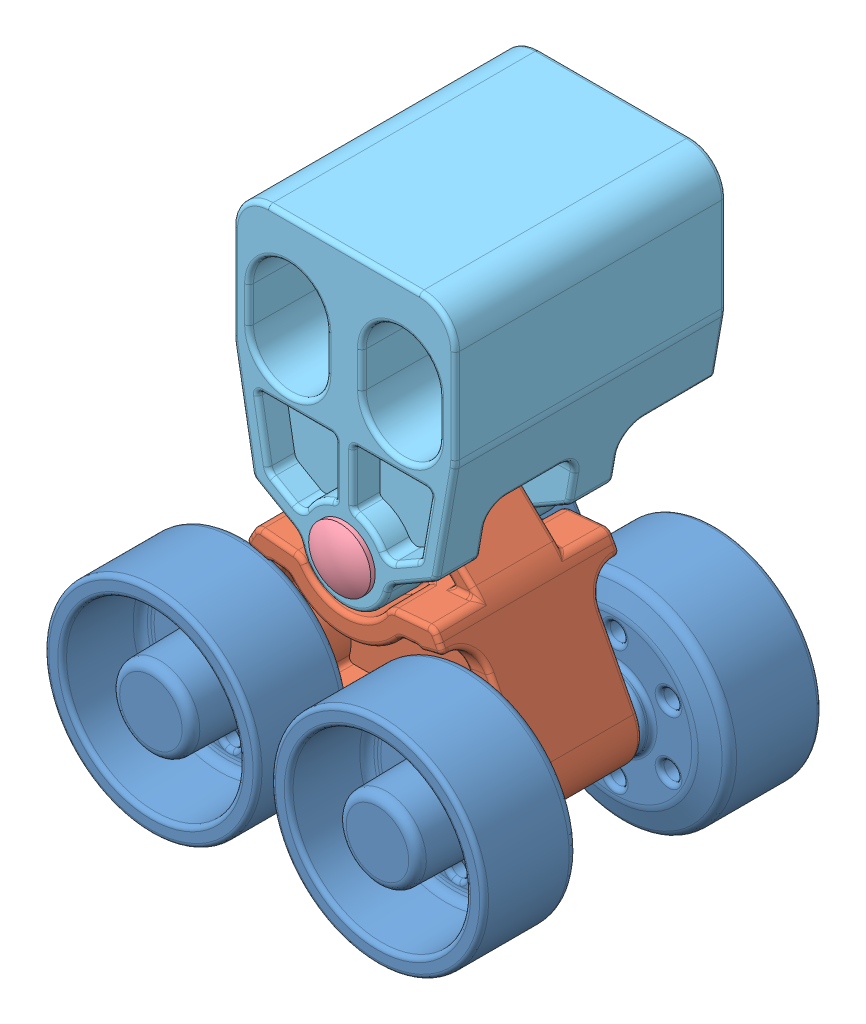
SolidWorks assembly IDLER-DOUBLE-WHEEL, configuration Default. Lengths in mm.
Overall size (49.5 59 39.51).
9 component instances, 5 part files, 0 mates.
Components (placement in the parent):
- IDLER-WHEEL-ROLLER-1: IDLER-WHEEL-ROLLER [Default] at (-12.75 4.5 6.5) x (0 0 1) z (0 1 0) size (12.5 24 24)
- IDLER-DOUBLE-WHEEL-SUPPORT-BOT-1: IDLER-DOUBLE-WHEEL-SUPPORT-BOT [Default] at origin size (34.5 27 20.12)
- IDLER-WHEEL-AXLE-1: IDLER-WHEEL-AXLE [Default] at (-12.75 4.5 0) size (4 4 34)
- IDLER-WHEEL-ROLLER-2: IDLER-WHEEL-ROLLER [Default] at (12.75 4.5 -6.5) x (0 0 -1) z (0 1 0) size (12.5 24 24)
- IDLER-WHEEL-AXLE-2: IDLER-WHEEL-AXLE [Default] at (12.75 4.5 0) size (4 4 34)
- IDLER-WHEEL-ROLLER-3: IDLER-WHEEL-ROLLER [Default] at (-12.75 4.5 -6.5) x (0 0 -1) z (0 1 0) size (12.5 24 24)
- IDLER-DOUBLE-WHEEL-RIVET-1: IDLER-DOUBLE-WHEEL-RIVET [Default] at (0 21.5 -12) x (-1 0 0) z (0 1 0) size (7 23.5 7)
- IDLER-DOUBLE-WHEEL-SUPPORT-TOP-1: IDLER-DOUBLE-WHEEL-SUPPORT-TOP [Default] at (0 43.5 0) size (25 35 30.51)
- IDLER-WHEEL-ROLLER-4: IDLER-WHEEL-ROLLER [Default] at (12.75 4.5 6.5) x (0 0 1) z (0 1 0) size (12.5 24 24)
